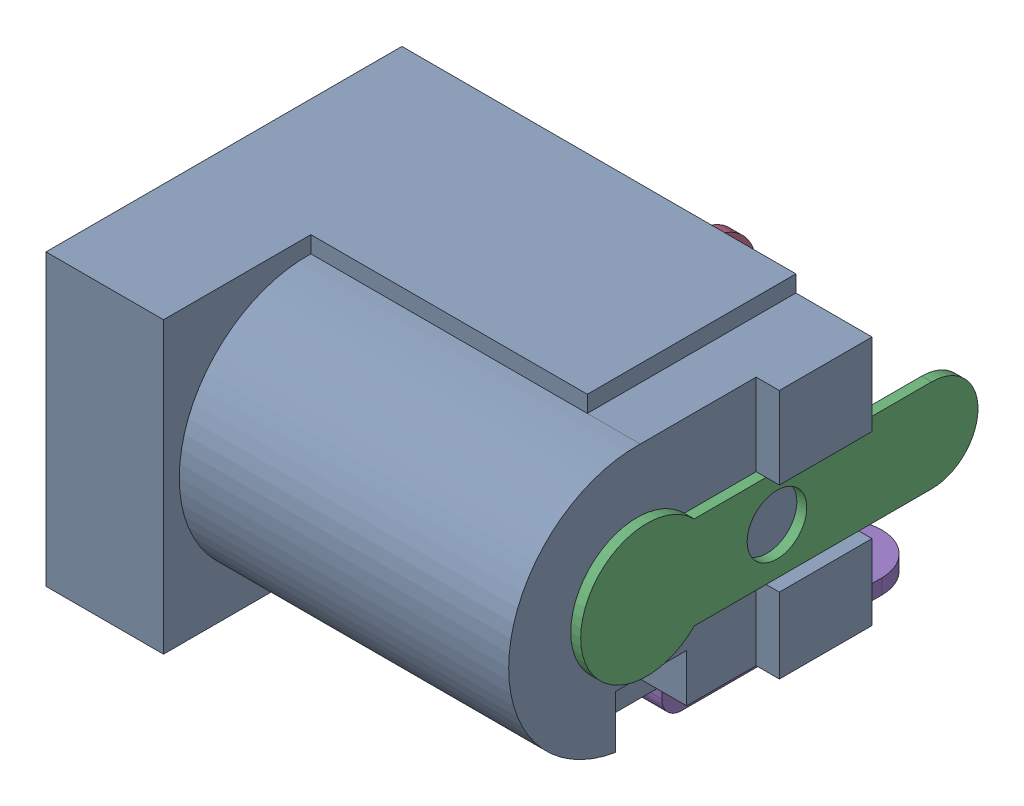
SolidWorks assembly 2.1mm DC Power Socket, configuration Default. Lengths in mm.
Overall size (14.2 9.7 14.75).
5 component instances, 5 part files, 0 mates.
Components (placement in the parent):
- 2.1mm DC Power Socket Housing-1: 2.1mm DC Power Socket Housing [Default] x (-1 0 0) z (0 0 1) size (14.2 8.75 10.75)
- 2.1mm DC Power Socket Pin-1: 2.1mm DC Power Socket Pin [Default] at (5.8 0 6.4) x (0 1 0) z (-1 0 0) size (3.45 3.45 8.5)
- Terminal 1-1: Terminal 1 [Default] at (9.95 0 6.4) x (0 1 0) z (1 0 0) size (4 12 0.3)
- Terminal 2-1: Terminal 2 [Default] at (2.95 0 0) x (1 0 0) z (0 0 -1) size (0.4 2.8 4)
- Terminal 3-1: Terminal 3 [Default] at (5.85 -4.375 4.05) x (0 1 0) z (1 0 0) size (0.95 7.9 2.5)
